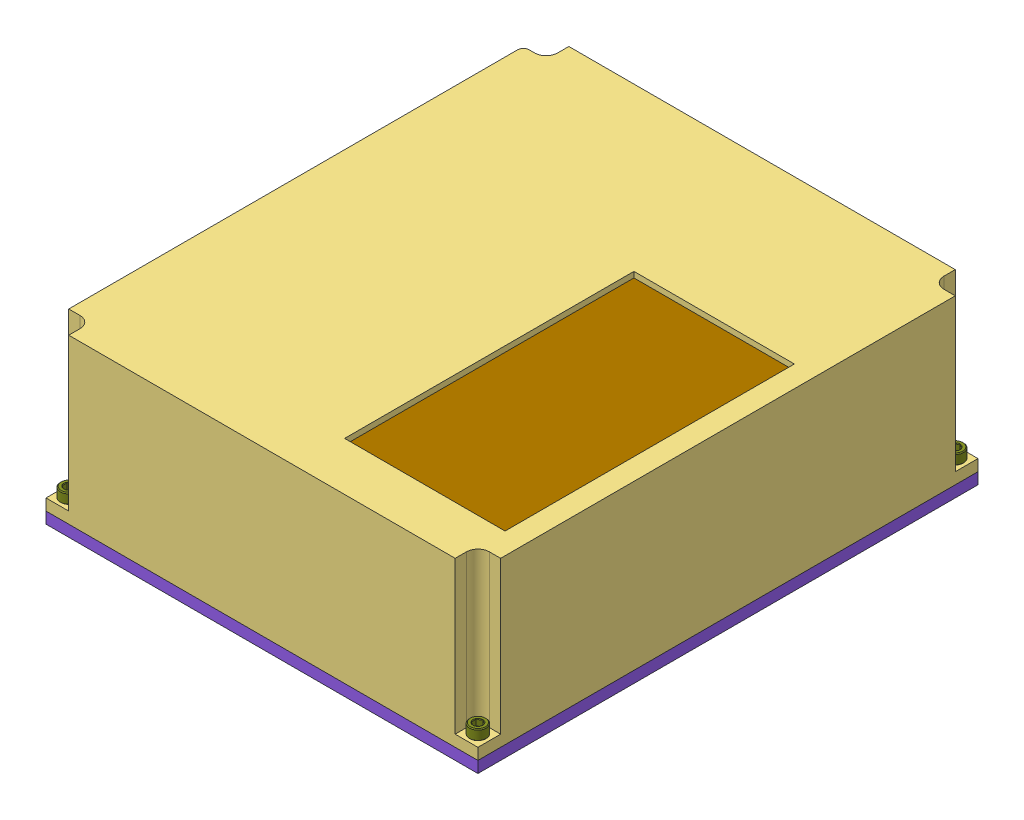
SolidWorks assembly Pointing Camera, configuration Default. Lengths in mm.
Overall size (120.65 87.31 139.7).
50 component instances, 21 part files, 56 mates.
Components (placement in the parent):
- Mirror X Assembly-1: Mirror X Assembly [Default] at (-12.3192 -4.7625 3.524) x (-0.707107 0 -0.707107) z (0.707107 0 -0.707107) size (26.61 80.4 14.78)
  - SH2141-5511-2: SH2141-5511 [Default] x (1 0 0) z (0 -1 0) size (14 14 55)
  - Square Mirror Mount-1: Square Mirror Mount [Default] at (0 27.7 0) x (-0.991445 0 -0.130526) z (-0.130526 0 0.991445) size (25.4 31.75 10.94)
  - Edmund 43-792-1: Edmund 43-792 [Default] at (0 27.5 0) x (0.991445 0 0.130526) z (0.130526 0 -0.991445) size (25 25 3)
- Mirror Y Assembly-1: Mirror Y Assembly [Default] at (32.1308 -3.175 3.524) x (0 0 1) z (-1 0 0) size (105 38.28 27.2)
  - Y Bearing Mount-1: Y Bearing Mount [Default] at (-40 25.908 0) x (0 0 -1) z (1 0 0) size (25.4 35.43 15.88)
  - Y Square Mirror Mount-1: Y Square Mirror Mount [Default] at (-12.3 25.908 0) x (0 0.707107 -0.707107) z (0 0.707107 0.707107) size (25.4 44.45 10.94)
  - Edmund 48-450-1: Edmund 48-450 [Default] at (0 25.908 0) x (1 0 0) z (0 -0.707107 -0.707107) size (50 35 3)
  - SH2141-5511-1: SH2141-5511 [Default] at (-40 25.908 0) x (0 1 0) z (-1 0 0) size (14 14 55)
  - 91292A005_TYPE 18-8 SS SOCKET HEAD CAP SCREW-1: 91292A005_TYPE 18-8 SS SOCKET HEAD CAP SCREW [91292A005] at (-41.825 20.158 5.75) x (0 0 1) z (-1 0 0) size (3.8 3.8 7.09)
  - 91292A005_TYPE 18-8 SS SOCKET HEAD CAP SCREW-2: 91292A005_TYPE 18-8 SS SOCKET HEAD CAP SCREW [91292A005] at (-41.825 20.158 -5.75) x (0 0 1) z (-1 0 0) size (3.8 3.8 7.09)
  - 91292A005_TYPE 18-8 SS SOCKET HEAD CAP SCREW-3: 91292A005_TYPE 18-8 SS SOCKET HEAD CAP SCREW [91292A005] at (-41.825 31.658 -5.75) x (0 0 1) z (-1 0 0) size (3.8 3.8 7.09)
  - 91292A005_TYPE 18-8 SS SOCKET HEAD CAP SCREW-4: 91292A005_TYPE 18-8 SS SOCKET HEAD CAP SCREW [91292A005] at (-41.825 31.658 5.75) x (0 0 1) z (-1 0 0) size (3.8 3.8 7.09)
- Optics Bench-1: Optics Bench [Default] at (0 -6.35 0) size (120.65 3.17 139.7)
- Edmund 32-741-1: Edmund 32-741 [Default] at (35.1125 37.9575 -3.175) size (48 3 84)
- Camera Assembly-1: Camera Assembly [Default] at (20.5321 3.4754 -91.8837) x (0 1 0) z (0 0 1) size (40.31 27.46 70.2)
  - Raspberry Pi Camera Module v2-1: Raspberry Pi Camera Module v2 [Default] at (21.6708 32.7592 14.0337) size (39.15 52.06 50.83)
  - PT-5020-1: PT-5020 [Default] at (19.2621 32.8513 26.7327) x (0.999854 -0.017096 0) z (-0.017096 -0.999854 0) size (27 52.8 27)
  - PT-LH024RPM-1: PT-LH024RPM [Default] at (19.2621 32.8513 15.0337) x (0 1 0) z (1 0 0) size (25 16 16)
  - Lens Mount-1: Lens Mount [Default] at (-6.6459 32.8513 48.8827) x (0 -1 0) z (0 0 1) size (25.4 38.1 15.88)
  - Camera Mount-2: Camera Mount [Default] at (-6.6459 32.8513 25.2087) x (0 -1 0) z (0 0 1) size (25.4 38.1 15.88)
  - 91292A005_TYPE 18-8 SS SOCKET HEAD CAP SCREW-1: 91292A005_TYPE 18-8 SS SOCKET HEAD CAP SCREW [91292A005] at (19.2621 22.3513 20.2087) x (-0.923728 -0.383049 0) z (0 0 -1) size (3.8 3.8 7.09)
  - 91292A005_TYPE 18-8 SS SOCKET HEAD CAP SCREW-2: 91292A005_TYPE 18-8 SS SOCKET HEAD CAP SCREW [91292A005] at (19.2621 43.3513 20.2087) x (-0.923728 -0.383049 0) z (0 0 -1) size (3.8 3.8 7.09)
  - 91292A005_TYPE 18-8 SS SOCKET HEAD CAP SCREW-3: 91292A005_TYPE 18-8 SS SOCKET HEAD CAP SCREW [91292A005] at (19.1661 22.3534 19.0837) size (3.8 3.8 7.09)
  - 91292A005_TYPE 18-8 SS SOCKET HEAD CAP SCREW-4: 91292A005_TYPE 18-8 SS SOCKET HEAD CAP SCREW [91292A005] at (19.1661 43.3534 19.0837) size (3.8 3.8 7.09)
- Raspberry_Pi_Zero_V1.3-1: Raspberry_Pi_Zero_V1.3 [Default] at (-27.3192 -6.385 -8.0576) x (0 0 -1) z (0 -1 0) size (65.7 30.6 4.49)
- 92196A106_18-8 STAINLESS STEEL SOCKET HEAD CAP SCREW-1: 92196A106_18-8 STAINLESS STEEL SOCKET HEAD CAP SCREW [92196A106] at (-12.3192 -6.3455 -55.701) x (1 0 0) z (0 -1 0) size (4.65 4.65 9.55)
- 92196A106_18-8 STAINLESS STEEL SOCKET HEAD CAP SCREW-5: 92196A106_18-8 STAINLESS STEEL SOCKET HEAD CAP SCREW [92196A106] at (32.1308 -6.35 -46.001) x (1 0 0) z (0 -1 0) size (4.65 4.65 9.55)
- Flat-Field Assembly-1: Flat-Field Assembly [Default] at (-70.7354 -8.3446 3.524) x (0 0 -1) z (1 0 0) size (28.99 39.03 16.73)
  - EL Panel Mount-1: EL Panel Mount [Default] at (3.3549 31.0776 38.5978) size (25.4 38.61 12.7)
  - EL Panel-1: EL Panel [Default] at (3.3549 31.0776 38.3438) size (25.4 19.05 0.4)
  - EL Panel Retainer-1: EL Panel Retainer [Default] at (3.3549 31.0776 38.7438) size (25.4 25.4 1.59)
  - 98511A111_LIGHTWEIGHT ALUMINUM SOCKET HEAD CAP SCREW-1: 98511A111_LIGHTWEIGHT ALUMINUM SOCKET HEAD CAP SCREW [98511A111] at (-7.4401 20.2826 35.5688) x (-0.923728 -0.383049 0) z (0 0 -1) size (3.56 3.56 7.46)
  - 98511A111_LIGHTWEIGHT ALUMINUM SOCKET HEAD CAP SCREW-2: 98511A111_LIGHTWEIGHT ALUMINUM SOCKET HEAD CAP SCREW [98511A111] at (14.1499 20.2826 35.5688) x (-0.923728 -0.383049 0) z (0 0 -1) size (3.56 3.56 7.46)
  - 98511A111_LIGHTWEIGHT ALUMINUM SOCKET HEAD CAP SCREW-3: 98511A111_LIGHTWEIGHT ALUMINUM SOCKET HEAD CAP SCREW [98511A111] at (14.1499 41.8726 35.5688) x (-0.923728 -0.383049 0) z (0 0 -1) size (3.56 3.56 7.46)
  - 98511A111_LIGHTWEIGHT ALUMINUM SOCKET HEAD CAP SCREW-4: 98511A111_LIGHTWEIGHT ALUMINUM SOCKET HEAD CAP SCREW [98511A111] at (-7.4401 41.8726 35.5688) x (-0.923728 -0.383049 0) z (0 0 -1) size (3.56 3.56 7.46)
- Optical Cover-1: Optical Cover [Photorealistic] at (3.175 -3.175 -19.05) size (120.65 45.72 139.7)
- 92196A106_18-8 STAINLESS STEEL SOCKET HEAD CAP SCREW-10: 92196A106_18-8 STAINLESS STEEL SOCKET HEAD CAP SCREW [92196A106] at (-21.8442 -6.3455 -49.351) x (1 0 0) z (0 -1 0) size (4.65 4.65 9.55)
- 92196A106_18-8 STAINLESS STEEL SOCKET HEAD CAP SCREW-11: 92196A106_18-8 STAINLESS STEEL SOCKET HEAD CAP SCREW [92196A106] at (-2.7942 -6.3455 -49.351) x (1 0 0) z (0 -1 0) size (4.65 4.65 9.55)
- 92196A106_18-8 STAINLESS STEEL SOCKET HEAD CAP SCREW-12: 92196A106_18-8 STAINLESS STEEL SOCKET HEAD CAP SCREW [92196A106] at (-21.8442 -6.3455 -73.025) x (1 0 0) z (0 -1 0) size (4.65 4.65 9.55)
- 92196A106_18-8 STAINLESS STEEL SOCKET HEAD CAP SCREW-13: 92196A106_18-8 STAINLESS STEEL SOCKET HEAD CAP SCREW [92196A106] at (-12.3192 -6.3455 -79.375) x (1 0 0) z (0 -1 0) size (4.65 4.65 9.55)
- 92196A106_18-8 STAINLESS STEEL SOCKET HEAD CAP SCREW-14: 92196A106_18-8 STAINLESS STEEL SOCKET HEAD CAP SCREW [92196A106] at (-2.7942 -6.3455 -73.025) x (1 0 0) z (0 -1 0) size (4.65 4.65 9.55)
- 92196A106_18-8 STAINLESS STEEL SOCKET HEAD CAP SCREW-15: 92196A106_18-8 STAINLESS STEEL SOCKET HEAD CAP SCREW [92196A106] at (22.6058 -6.35 -39.651) x (1 0 0) z (0 -1 0) size (4.65 4.65 9.55)
- 92196A106_18-8 STAINLESS STEEL SOCKET HEAD CAP SCREW-16: 92196A106_18-8 STAINLESS STEEL SOCKET HEAD CAP SCREW [92196A106] at (41.6558 -6.35 -39.651) x (1 0 0) z (0 -1 0) size (4.65 4.65 9.55)
- 92196A106_18-8 STAINLESS STEEL SOCKET HEAD CAP SCREW-17: 92196A106_18-8 STAINLESS STEEL SOCKET HEAD CAP SCREW [92196A106] at (-41.6626 -6.35 9.6941) x (1 0 0) z (0 -1 0) size (4.65 4.65 9.55)
- 92196A106_18-8 STAINLESS STEEL SOCKET HEAD CAP SCREW-18: 92196A106_18-8 STAINLESS STEEL SOCKET HEAD CAP SCREW [92196A106] at (-41.6626 -6.35 -9.3559) x (1 0 0) z (0 -1 0) size (4.65 4.65 9.55)
- 92196A106_18-8 STAINLESS STEEL SOCKET HEAD CAP SCREW-19: 92196A106_18-8 STAINLESS STEEL SOCKET HEAD CAP SCREW [92196A106] at (60.325 -6.35 47.625) x (1 0 0) z (0 -1 0) size (4.65 4.65 9.55)
- 92196A106_18-8 STAINLESS STEEL SOCKET HEAD CAP SCREW-20: 92196A106_18-8 STAINLESS STEEL SOCKET HEAD CAP SCREW [92196A106] at (60.325 -6.35 -85.725) x (1 0 0) z (0 -1 0) size (4.65 4.65 9.55)
- 92196A106_18-8 STAINLESS STEEL SOCKET HEAD CAP SCREW-21: 92196A106_18-8 STAINLESS STEEL SOCKET HEAD CAP SCREW [92196A106] at (-53.975 -6.35 47.625) x (1 0 0) z (0 -1 0) size (4.65 4.65 9.55)
- 92196A106_18-8 STAINLESS STEEL SOCKET HEAD CAP SCREW-22: 92196A106_18-8 STAINLESS STEEL SOCKET HEAD CAP SCREW [92196A106] at (-53.975 -6.35 -85.725) x (1 0 0) z (0 -1 0) size (4.65 4.65 9.55)
Mates (geometry in assembly coordinates):
- Coincident4: coincident anti-aligned: plane of ? through (-29.5049 -3.175 4.6348) normal (0 -1 0); plane of Optics Bench-1 through (0 -3.175 0) normal (0 1 0)
- Coincident5: coincident anti-aligned: plane of Mirror Y Assembly-1/Y Bearing Mount-1 through (19.4308 -3.175 -33.301) normal (0 -1 0); plane of Optics Bench-1 through (0 -3.175 0) normal (0 1 0)
- Angle1: planar angle = 2.356194 rad aligned: plane of ? through (-20.5247 17.653 13.615) normal (0.707107 0 -0.707107); plane of Optics Bench-1 through (-50.8 -3.175 50.8) normal (0 0 1)
- Distance1: distance = 44.45 mm: axis of Mirror Y Assembly-1/Y Square Mirror Mount-1 through (34.1607 30.48 -21.6204) axis (0 0 -1); axis of ? through (-10.2893 18.0325 3.3796) axis (0 -1 0)
- Concentric1: concentric anti-aligned: cylinder of ? through (-10.2893 -6.6675 3.3796) axis (0 -1 0) radius 6.35; cylinder of Optics Bench-1 through (-10.2893 -6.35 3.3796) axis (0 1 0) radius 6.35
- Concentric2: concentric aligned: cylinder of Camera Assembly-1/PT-5020-1 through (-12.3192 22.7375 -65.151) axis (0 0 -1) radius 8.5; line of assembly
- Parallel4: parallel aligned: plane of Optics Bench-1 through (0 -3.175 0) normal (0 1 0); plane of Camera Assembly-1/Raspberry Pi Camera Module v2-1 through (-1.8213 37.1415 -77.85) normal (0 1 0)
- Coincident24: coincident anti-aligned: plane of Camera Assembly-1/Lens Mount-1 through (0.3808 0.0045 -58.876) normal (0 1 0); plane of 92196A106_18-8 STAINLESS STEEL SOCKET HEAD CAP SCREW-1 through (-12.3192 0.0045 -55.701) normal (0 -1 0)
- Concentric8: concentric anti-aligned: cylinder of Camera Assembly-1/Lens Mount-1 through (-12.3192 0.0045 -55.701) axis (0 1 0) radius 1.4732; cylinder of 92196A106_18-8 STAINLESS STEEL SOCKET HEAD CAP SCREW-1 through (-12.3192 2.8493 -55.701) axis (0 -1 0) radius 2.3241
- Coincident27: coincident anti-aligned: plane of Mirror Y Assembly-1/Y Bearing Mount-1 through (19.4308 0 -49.176) normal (0 1 0); plane of 92196A106_18-8 STAINLESS STEEL SOCKET HEAD CAP SCREW-5 through (32.1308 0 -46.001) normal (0 -1 0)
- Concentric10: concentric anti-aligned: cylinder of Mirror Y Assembly-1/Y Bearing Mount-1 through (32.1308 0 -46.001) axis (0 1 0) radius 1.4732; cylinder of 92196A106_18-8 STAINLESS STEEL SOCKET HEAD CAP SCREW-5 through (32.1308 2.8448 -46.001) axis (0 -1 0) radius 2.3241
- Coincident29: coincident anti-aligned: plane of Optics Bench-1 through (0 -3.175 0) normal (0 1 0); plane of Flat-Field Assembly-1/EL Panel Mount-1 through (-32.1376 -3.175 -12.5309) normal (0 -1 0)
- Coincident30: coincident: plane of Flat-Field Assembly-1 through (-70.7354 -8.3446 3.524) normal (0 0 -1); point of assembly
- Coincident32: coincident anti-aligned: plane of Optics Bench-1 through (0 -3.175 0) normal (0 1 0); plane of Optical Cover-1 through (3.175 -3.175 -19.05) normal (0 -1 0)
- Coincident33: coincident aligned: plane of Optics Bench-1 through (-57.15 -146.1942 -88.9) normal (-1 0 0); plane of Optical Cover-1 through (-57.15 42.545 -88.9) normal (-1 0 0)
- Coincident34: coincident aligned: plane of Optics Bench-1 through (-50.8 -3.175 50.8) normal (0 0 1); plane of Optical Cover-1 through (-57.15 42.545 50.8) normal (0 0 1)
- Coincident36: coincident anti-aligned: plane of Edmund 32-741-1 through (35.1125 40.9575 -3.175) normal (0 1 0); plane of Optical Cover-1 through (3.175 40.9575 -19.05) normal (0 -1 0)
- Coincident37: coincident anti-aligned: plane of Edmund 32-741-1 through (59.1125 40.9575 -45.175) normal (1 0 0); plane of Optical Cover-1 through (59.1125 37.9575 -45.175) normal (-1 0 0)
- Coincident38: coincident anti-aligned: plane of Edmund 32-741-1 through (11.1125 40.9575 -45.175) normal (0 0 -1); plane of Optical Cover-1 through (11.1125 37.9575 -45.175) normal (0 0 1)
- Concentric12: concentric anti-aligned: cylinder of Camera Assembly-1/Lens Mount-1 through (-21.8442 0.0045 -49.351) axis (0 1 0) radius 1.4732; cylinder of 92196A106_18-8 STAINLESS STEEL SOCKET HEAD CAP SCREW-10 through (-21.8442 2.8493 -49.351) axis (0 -1 0) radius 2.3241
- Concentric13: concentric anti-aligned: cylinder of Camera Assembly-1/Lens Mount-1 through (-2.7942 0.0045 -49.351) axis (0 1 0) radius 1.4732; cylinder of 92196A106_18-8 STAINLESS STEEL SOCKET HEAD CAP SCREW-11 through (-2.7942 2.8493 -49.351) axis (0 -1 0) radius 2.3241
- Coincident40: coincident anti-aligned: plane of Camera Assembly-1/Lens Mount-1 through (0.3808 0.0045 -58.876) normal (0 1 0); plane of 92196A106_18-8 STAINLESS STEEL SOCKET HEAD CAP SCREW-11 through (-2.7942 0.0045 -49.351) normal (0 -1 0)
- Coincident41: coincident anti-aligned: plane of Camera Assembly-1/Lens Mount-1 through (0.3808 0.0045 -58.876) normal (0 1 0); plane of 92196A106_18-8 STAINLESS STEEL SOCKET HEAD CAP SCREW-10 through (-21.8442 0.0045 -49.351) normal (0 -1 0)
- Concentric14: concentric anti-aligned: cylinder of Camera Assembly-1/Camera Mount-2 through (-2.7942 0.0045 -73.025) axis (0 1 0) radius 1.4732; cylinder of 92196A106_18-8 STAINLESS STEEL SOCKET HEAD CAP SCREW-14 through (-2.7942 2.8493 -73.025) axis (0 -1 0) radius 2.3241
- Concentric15: concentric anti-aligned: cylinder of Camera Assembly-1/Camera Mount-2 through (-12.3192 0.0045 -79.375) axis (0 1 0) radius 1.4732; cylinder of 92196A106_18-8 STAINLESS STEEL SOCKET HEAD CAP SCREW-13 through (-12.3192 2.8493 -79.375) axis (0 -1 0) radius 2.3241
- Concentric16: concentric anti-aligned: cylinder of Camera Assembly-1/Camera Mount-2 through (-21.8442 0.0045 -73.025) axis (0 1 0) radius 1.4732; cylinder of 92196A106_18-8 STAINLESS STEEL SOCKET HEAD CAP SCREW-12 through (-21.8442 2.8493 -73.025) axis (0 -1 0) radius 2.3241
- Coincident42: coincident anti-aligned: plane of Camera Assembly-1/Camera Mount-2 through (0.3808 0.0045 -82.55) normal (0 1 0); plane of 92196A106_18-8 STAINLESS STEEL SOCKET HEAD CAP SCREW-14 through (-2.7942 0.0045 -73.025) normal (0 -1 0)
- Coincident43: coincident anti-aligned: plane of Camera Assembly-1/Camera Mount-2 through (0.3808 0.0045 -82.55) normal (0 1 0); plane of 92196A106_18-8 STAINLESS STEEL SOCKET HEAD CAP SCREW-13 through (-12.3192 0.0045 -79.375) normal (0 -1 0)
- Coincident44: coincident anti-aligned: plane of Camera Assembly-1/Camera Mount-2 through (0.3808 0.0045 -82.55) normal (0 1 0); plane of 92196A106_18-8 STAINLESS STEEL SOCKET HEAD CAP SCREW-12 through (-21.8442 0.0045 -73.025) normal (0 -1 0)
- Coincident45: coincident anti-aligned: plane of Flat-Field Assembly-1/EL Panel Mount-1 through (-44.8376 0 -12.5309) normal (0 1 0); plane of 92196A106_18-8 STAINLESS STEEL SOCKET HEAD CAP SCREW-17 through (-41.6626 0 9.6941) normal (0 -1 0)
- Coincident46: coincident anti-aligned: plane of Flat-Field Assembly-1/EL Panel Mount-1 through (-44.8376 0 -12.5309) normal (0 1 0); plane of 92196A106_18-8 STAINLESS STEEL SOCKET HEAD CAP SCREW-18 through (-41.6626 0 -9.3559) normal (0 -1 0)
- Concentric17: concentric anti-aligned: cylinder of Flat-Field Assembly-1/EL Panel Mount-1 through (-41.6626 0 9.6941) axis (0 1 0) radius 1.4732; cylinder of 92196A106_18-8 STAINLESS STEEL SOCKET HEAD CAP SCREW-17 through (-41.6626 2.8448 9.6941) axis (0 -1 0) radius 2.3241
- Concentric18: concentric anti-aligned: cylinder of Flat-Field Assembly-1/EL Panel Mount-1 through (-41.6626 0 -9.3559) axis (0 1 0) radius 1.4732; cylinder of 92196A106_18-8 STAINLESS STEEL SOCKET HEAD CAP SCREW-18 through (-41.6626 2.8448 -9.3559) axis (0 -1 0) radius 2.3241
- Coincident47: coincident anti-aligned: plane of Mirror Y Assembly-1/Y Bearing Mount-1 through (19.4308 0 -49.176) normal (0 1 0); plane of 92196A106_18-8 STAINLESS STEEL SOCKET HEAD CAP SCREW-15 through (22.6058 0 -39.651) normal (0 -1 0)
- Coincident48: coincident anti-aligned: plane of Mirror Y Assembly-1/Y Bearing Mount-1 through (19.4308 0 -49.176) normal (0 1 0); plane of 92196A106_18-8 STAINLESS STEEL SOCKET HEAD CAP SCREW-16 through (41.6558 0 -39.651) normal (0 -1 0)
- Concentric19: concentric anti-aligned: cylinder of Mirror Y Assembly-1/Y Bearing Mount-1 through (22.6058 0 -39.651) axis (0 1 0) radius 1.5875; cylinder of 92196A106_18-8 STAINLESS STEEL SOCKET HEAD CAP SCREW-15 through (22.6058 2.8448 -39.651) axis (0 -1 0) radius 2.3241
- Concentric20: concentric anti-aligned: cylinder of Mirror Y Assembly-1/Y Bearing Mount-1 through (41.6558 0 -39.651) axis (0 1 0) radius 1.5875; cylinder of 92196A106_18-8 STAINLESS STEEL SOCKET HEAD CAP SCREW-16 through (41.6558 2.8448 -39.651) axis (0 -1 0) radius 2.3241
- Concentric21: concentric anti-aligned: cylinder of Optical Cover-1 through (-53.975 42.545 -85.725) axis (0 1 0) radius 1.4732; cylinder of 92196A106_18-8 STAINLESS STEEL SOCKET HEAD CAP SCREW-22 through (-53.975 2.8448 -85.725) axis (0 -1 0) radius 2.3241
- Coincident49: coincident anti-aligned: plane of Optical Cover-1 through (3.175 0 -19.05) normal (0 1 0); plane of 92196A106_18-8 STAINLESS STEEL SOCKET HEAD CAP SCREW-22 through (-53.975 0 -85.725) normal (0 -1 0)
- Concentric22: concentric anti-aligned: cylinder of Optical Cover-1 through (-53.975 42.545 47.625) axis (0 1 0) radius 1.4732; cylinder of 92196A106_18-8 STAINLESS STEEL SOCKET HEAD CAP SCREW-21 through (-53.975 2.8448 47.625) axis (0 -1 0) radius 2.3241
- Coincident50: coincident anti-aligned: plane of Optical Cover-1 through (3.175 0 -19.05) normal (0 1 0); plane of 92196A106_18-8 STAINLESS STEEL SOCKET HEAD CAP SCREW-21 through (-53.975 0 47.625) normal (0 -1 0)
- Concentric23: concentric anti-aligned: cylinder of Optical Cover-1 through (60.325 42.545 47.625) axis (0 1 0) radius 1.4732; cylinder of 92196A106_18-8 STAINLESS STEEL SOCKET HEAD CAP SCREW-19 through (60.325 2.8448 47.625) axis (0 -1 0) radius 2.3241
- Coincident51: coincident anti-aligned: plane of Optical Cover-1 through (3.175 0 -19.05) normal (0 1 0); plane of 92196A106_18-8 STAINLESS STEEL SOCKET HEAD CAP SCREW-19 through (60.325 0 47.625) normal (0 -1 0)
- Concentric24: concentric anti-aligned: cylinder of Optical Cover-1 through (60.325 42.545 -85.725) axis (0 1 0) radius 1.4732; cylinder of 92196A106_18-8 STAINLESS STEEL SOCKET HEAD CAP SCREW-20 through (60.325 2.8448 -85.725) axis (0 -1 0) radius 2.3241
- Coincident52: coincident anti-aligned: plane of Optical Cover-1 through (3.175 0 -19.05) normal (0 1 0); plane of 92196A106_18-8 STAINLESS STEEL SOCKET HEAD CAP SCREW-20 through (60.325 0 -85.725) normal (0 -1 0)
- Distance2: distance = 6.35 mm aligned: plane of Camera Assembly-1/Camera Mount-2 through (0.3808 -3.1705 -82.55) normal (0 0 -1); plane of Optics Bench-1 through (-50.8 -163.4403 -88.9) normal (0 0 -1)
- Coincident62: coincident aligned: plane of Mirror X Assembly-1 through (-12.3192 -4.7625 3.524) normal (0 0 1); plane of Mirror Y Assembly-1/Edmund 48-450-1
- Coincident63: coincident anti-aligned: plane of Mirror X Assembly-1/SH2141-5511-2 through (-12.3192 -4.7625 3.524) normal (0 1 0); plane of Optics Bench-1 through (-53.975 -4.7625 -85.725) normal (0 -1 0)
- Coincident64: coincident: plane of Mirror X Assembly-1; axis of Camera Assembly-1/PT-5020-1 through (-12.3192 22.7375 -20.351) axis (0 0 -1)
- Distance4: distance = 15.875 mm: axis of Mirror X Assembly-1/SH2141-5511-2 through (-12.3192 9.7375 3.524) axis (0 -1 0); plane of Camera Assembly-1/PT-5020-1 through (-12.55 9.2395 -12.351) normal (0 0 1)
- Distance5: distance = 31.75 mm anti-aligned: plane of Mirror X Assembly-1; plane of Mirror Y Assembly-1/Y Bearing Mount-1 through (19.4308 32.258 -33.301) normal (-1 0 0)
- Parallel5: parallel aligned: plane of Camera Assembly-1/Lens Mount-1 through (-25.0192 -3.1705 -43.001) normal (-1 0 0); plane of Flat-Field Assembly-1/EL Panel Mount-1 through (-35.3126 0 -12.5309) normal (-1 0 0)
- Parallel6: parallel anti-aligned: plane of Optics Bench-1 through (-53.975 -4.7625 -85.725) normal (0 -1 0); plane of Raspberry_Pi_Zero_V1.3-1 through (-24.3192 -6.385 -70.0576) normal (0 1 0)
- Parallel7: parallel aligned: plane of Optics Bench-1 through (63.5 -6.35 -88.9) normal (1 0 0); plane of Raspberry_Pi_Zero_V1.3-1 through (2.6808 -7.385 -11.0576) normal (1 0 0)
- Coincident71: coincident anti-aligned: plane of Optics Bench-1 through (0 -6.35 0) normal (0 -1 0); plane of Raspberry_Pi_Zero_V1.3-1 through (-0.8192 -6.35 -69.5576) normal (0 1 0)
- Coincident73: coincident anti-aligned: plane of Camera Assembly-1/Camera Mount-2 through (-12.3192 -3.1705 -66.675) normal (1 0 0); plane of Raspberry_Pi_Zero_V1.3-1
